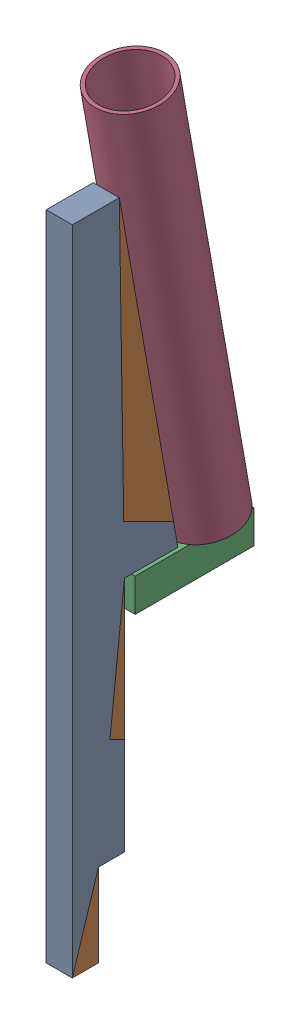
SolidWorks assembly SupportEau v9, configuration Défaut. Lengths in mm.
Overall size (60 625.45 150.06).
3 component instances, 3 part files, 0 mates.
Components (placement in the parent):
- SupportEau1 v7-1: SupportEau1 v7 [Défaut] at (1645.9553 0 1119.902) x (0 0 -1) z (0 -1 0) size (89 22 550)
- SupportEau2 v5-1: SupportEau2 v5 [Défaut] at (1656.9553 242 1055.902) x (0 0 -1) z (1 0 0) size (100 28 28)
- SupportEau3 v3-1: SupportEau3 v3 [Défaut] at (1656.9553 620.2395 1060.165) x (0 0.173648 -0.984808) z (-1 0 0) size (60 350 60)
